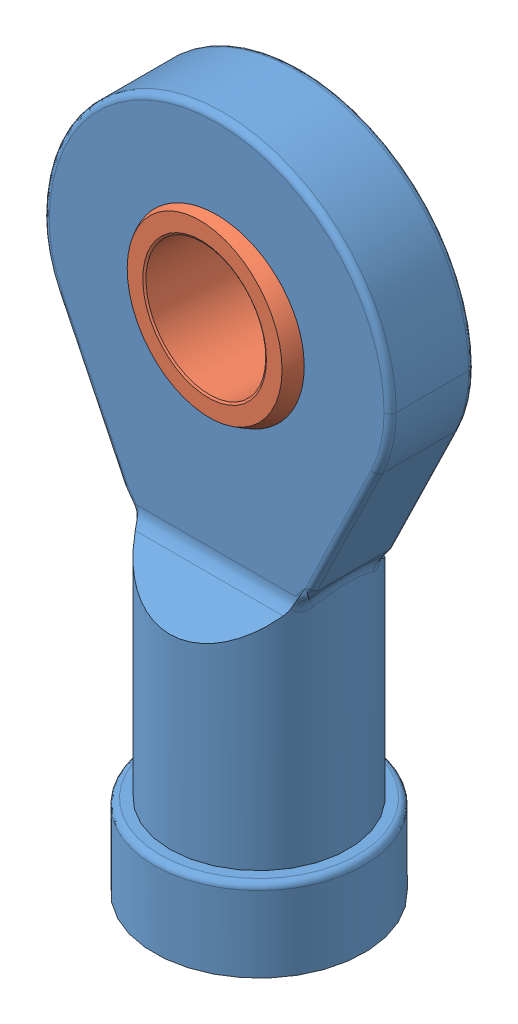
SolidWorks assembly Assem2, configuration Default. Lengths in mm.
Overall size (43 86 25.98).
2 component instances, 2 part files, 1 mates.
Components (placement in the parent):
- Rod_End_EBRI_10R-1: Rod_End_EBRI_10R [Default] at (36.3685 5.5292 61.283) size (43 86 25.98)
- Ball_EBRI_10R-1: Ball_EBRI_10R [Default] at (36.3685 70.0299 61.283) x (0.997961 -0.010235 0.063004) z (-0.062993 0.0014 0.998013) size (24.13 24.13 12.7)
Mates (geometry in assembly coordinates):
- Concentric1: concentric: sphere of Rod_End_EBRI_10R-1; sphere of Ball_EBRI_10R-1
